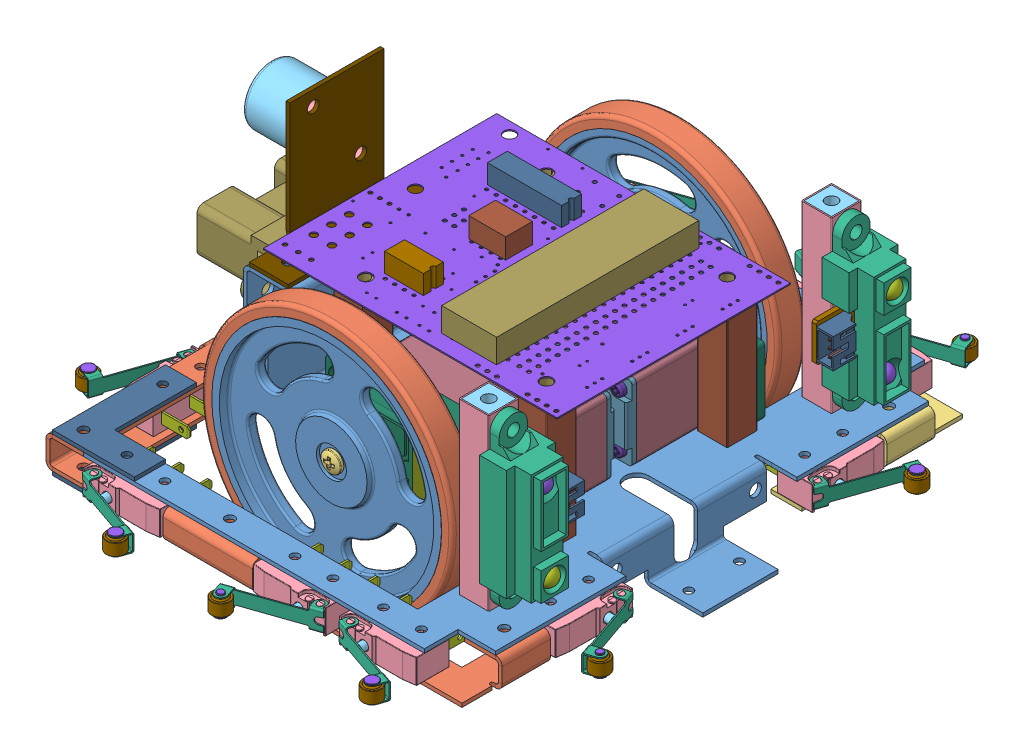
SolidWorks assembly SALbot, configuration Default. Lengths in mm.
Overall size (139.7 93.66 163.86).
225 component instances, 69 part files, 50 mates.
Components (placement in the parent):
- Chassis_alternativo-1: Chassis_alternativo [Default] at (-2.6157 -5.2715 -10.4768) size (139.7 34.48 163.86)
  - Chassis1_alternativa-1: Chassis1_alternativa [Default] at (-16.5911 3.3668 6.4675) size (122.56 34.48 132.92)
  - Chassis1_alternativa_1-1: Chassis1_alternativa_1 [Default] at (3.1589 -4.1332 51.6075) size (112.22 8.5 50.92)
  - Chassis1_alternativa_2-1: Chassis1_alternativa_2 [Default] at (3.1589 -3.1332 -38.6725) x (1 0 0) z (0 0 -1) size (112.22 8.5 50.92)
  - Switch-1: Switch [Default] at (-30.7928 -1.6984 -57.0433) x (1 0 0) z (0 1 0) size (22.89 29.47 6.5)
    - corpo-1: corpo [Default] at (1.1317 -3.5508 1.8152) size (19.85 9.5 6.5)
    - botao-1: botao [Default] at (-1.9933 4.9492 1.8152) size (2.28 2.9 2.2)
    - haste-1: haste [Default] at (1.6775 9.3883 1.8152) x (-0.945111 -0.326749 0) z (0 0 -1) size (21.6 7.58 5.4)
    - pinsw-1: pinsw [Default] at (-6.3683 -11.0508 1.8152) x (0 0 -1) z (1 0 0) size (2.85 8.5 0.5)
    - pino_haste-1: pino_haste [Default] at (9.4909 15.2506 1.8152) x (-0.923728 -0.383049 0) z (0 0 -1) size (3.2 3.2 5.25)
    - roda-1: roda [Default] at (9.4909 15.2506 1.8152) x (-0.923728 -0.383049 0) z (0 0 -1) size (4.85 4.85 3.95)
    - pinsw-3: pinsw [Default] at (1.1317 -11.0508 1.8152) x (0 0 -1) z (1 0 0) size (2.85 8.5 0.5)
    - pinsw-5: pinsw [Default] at (8.6317 -11.0508 1.8152) x (0 0 -1) z (1 0 0) size (2.85 8.5 0.5)
  - Switch-2: Switch [Default] at (16.1106 1.932 -57.0433) x (-1 0 0) z (0 -1 0) size (22.89 29.47 6.5)
    - corpo-1: corpo [Default] at (1.1317 -3.5508 1.8152) size (19.85 9.5 6.5)
    - botao-1: botao [Default] at (-1.9933 4.9492 1.8152) size (2.28 2.9 2.2)
    - haste-1: haste [Default] at (1.6775 9.3883 1.8152) x (-0.945111 -0.326749 0) z (0 0 -1) size (21.6 7.58 5.4)
    - pinsw-1: pinsw [Default] at (-6.3683 -11.0508 1.8152) x (0 0 -1) z (1 0 0) size (2.85 8.5 0.5)
    - pino_haste-1: pino_haste [Default] at (9.4909 15.2506 1.8152) x (-0.923728 -0.383049 0) z (0 0 -1) size (3.2 3.2 5.25)
    - roda-1: roda [Default] at (9.4909 15.2506 1.8152) x (-0.923728 -0.383049 0) z (0 0 -1) size (4.85 4.85 3.95)
    - pinsw-3: pinsw [Default] at (1.1317 -11.0508 1.8152) x (0 0 -1) z (1 0 0) size (2.85 8.5 0.5)
    - pinsw-5: pinsw [Default] at (8.6317 -11.0508 1.8152) x (0 0 -1) z (1 0 0) size (2.85 8.5 0.5)
  - Switch-3: Switch [Default] at (55.4648 -1.6984 39.0858) x (0 0 1) z (0 1 0) size (22.89 29.47 6.5)
    - corpo-1: corpo [Default] at (1.1317 -3.5508 1.8152) size (19.85 9.5 6.5)
    - botao-1: botao [Default] at (-1.9933 4.9492 1.8152) size (2.28 2.9 2.2)
    - haste-1: haste [Default] at (1.6775 9.3883 1.8152) x (-0.945111 -0.326749 0) z (0 0 -1) size (21.6 7.58 5.4)
    - pinsw-1: pinsw [Default] at (-6.3683 -11.0508 1.8152) x (0 0 -1) z (1 0 0) size (2.85 8.5 0.5)
    - pino_haste-1: pino_haste [Default] at (9.4909 15.2506 1.8152) x (-0.923728 -0.383049 0) z (0 0 -1) size (3.2 3.2 5.25)
    - roda-1: roda [Default] at (9.4909 15.2506 1.8152) x (-0.923728 -0.383049 0) z (0 0 -1) size (4.85 4.85 3.95)
    - pinsw-3: pinsw [Default] at (1.1317 -11.0508 1.8152) x (0 0 -1) z (1 0 0) size (2.85 8.5 0.5)
    - pinsw-5: pinsw [Default] at (8.6317 -11.0508 1.8152) x (0 0 -1) z (1 0 0) size (2.85 8.5 0.5)
  - Switch-4: Switch [Default] at (37.3472 -1.6984 -57.0433) x (1 0 0) z (0 1 0) size (22.89 29.47 6.5)
    - corpo-1: corpo [Default] at (1.1317 -3.5508 1.8152) size (19.85 9.5 6.5)
    - botao-1: botao [Default] at (-1.9933 4.9492 1.8152) size (2.28 2.9 2.2)
    - haste-1: haste [Default] at (1.6775 9.3883 1.8152) x (-0.945111 -0.326749 0) z (0 0 -1) size (21.6 7.58 5.4)
    - pinsw-1: pinsw [Default] at (-6.3683 -11.0508 1.8152) x (0 0 -1) z (1 0 0) size (2.85 8.5 0.5)
    - pino_haste-1: pino_haste [Default] at (9.4909 15.2506 1.8152) x (-0.923728 -0.383049 0) z (0 0 -1) size (3.2 3.2 5.25)
    - roda-1: roda [Default] at (9.4909 15.2506 1.8152) x (-0.923728 -0.383049 0) z (0 0 -1) size (4.85 4.85 3.95)
    - pinsw-3: pinsw [Default] at (1.1317 -11.0508 1.8152) x (0 0 -1) z (1 0 0) size (2.85 8.5 0.5)
    - pinsw-5: pinsw [Default] at (8.6317 -11.0508 1.8152) x (0 0 -1) z (1 0 0) size (2.85 8.5 0.5)
  - Switch-5: Switch [Default] at (-30.7928 1.932 69.9784) x (1 0 0) z (0 -1 0) size (22.89 29.47 6.5)
    - corpo-1: corpo [Default] at (1.1317 -3.5508 1.8152) size (19.85 9.5 6.5)
    - botao-1: botao [Default] at (-1.9933 4.9492 1.8152) size (2.28 2.9 2.2)
    - haste-1: haste [Default] at (1.6775 9.3883 1.8152) x (-0.945111 -0.326749 0) z (0 0 -1) size (21.6 7.58 5.4)
    - pinsw-1: pinsw [Default] at (-6.3683 -11.0508 1.8152) x (0 0 -1) z (1 0 0) size (2.85 8.5 0.5)
    - pino_haste-1: pino_haste [Default] at (9.4909 15.2506 1.8152) x (-0.923728 -0.383049 0) z (0 0 -1) size (3.2 3.2 5.25)
    - roda-1: roda [Default] at (9.4909 15.2506 1.8152) x (-0.923728 -0.383049 0) z (0 0 -1) size (4.85 4.85 3.95)
    - pinsw-3: pinsw [Default] at (1.1317 -11.0508 1.8152) x (0 0 -1) z (1 0 0) size (2.85 8.5 0.5)
    - pinsw-5: pinsw [Default] at (8.6317 -11.0508 1.8152) x (0 0 -1) z (1 0 0) size (2.85 8.5 0.5)
  - Switch-6: Switch [Default] at (37.3472 1.932 69.9784) x (1 0 0) z (0 -1 0) size (22.89 29.47 6.5)
    - corpo-1: corpo [Default] at (1.1317 -3.5508 1.8152) size (19.85 9.5 6.5)
    - botao-1: botao [Default] at (-1.9933 4.9492 1.8152) size (2.28 2.9 2.2)
    - haste-1: haste [Default] at (1.6775 9.3883 1.8152) x (-0.945111 -0.326749 0) z (0 0 -1) size (21.6 7.58 5.4)
    - pinsw-1: pinsw [Default] at (-6.3683 -11.0508 1.8152) x (0 0 -1) z (1 0 0) size (2.85 8.5 0.5)
    - pino_haste-1: pino_haste [Default] at (9.4909 15.2506 1.8152) x (-0.923728 -0.383049 0) z (0 0 -1) size (3.2 3.2 5.25)
    - roda-1: roda [Default] at (9.4909 15.2506 1.8152) x (-0.923728 -0.383049 0) z (0 0 -1) size (4.85 4.85 3.95)
    - pinsw-3: pinsw [Default] at (1.1317 -11.0508 1.8152) x (0 0 -1) z (1 0 0) size (2.85 8.5 0.5)
    - pinsw-5: pinsw [Default] at (8.6317 -11.0508 1.8152) x (0 0 -1) z (1 0 0) size (2.85 8.5 0.5)
  - Switch-7: Switch [Default] at (55.4648 1.932 -26.1507) x (0 0 -1) z (0 -1 0) size (22.89 29.47 6.5)
    - corpo-1: corpo [Default] at (1.1317 -3.5508 1.8152) size (19.85 9.5 6.5)
    - botao-1: botao [Default] at (-1.9933 4.9492 1.8152) size (2.28 2.9 2.2)
    - haste-1: haste [Default] at (1.6775 9.3883 1.8152) x (-0.945111 -0.326749 0) z (0 0 -1) size (21.6 7.58 5.4)
    - pinsw-1: pinsw [Default] at (-6.3683 -11.0508 1.8152) x (0 0 -1) z (1 0 0) size (2.85 8.5 0.5)
    - pino_haste-1: pino_haste [Default] at (9.4909 15.2506 1.8152) x (-0.923728 -0.383049 0) z (0 0 -1) size (3.2 3.2 5.25)
    - roda-1: roda [Default] at (9.4909 15.2506 1.8152) x (-0.923728 -0.383049 0) z (0 0 -1) size (4.85 4.85 3.95)
    - pinsw-3: pinsw [Default] at (1.1317 -11.0508 1.8152) x (0 0 -1) z (1 0 0) size (2.85 8.5 0.5)
    - pinsw-5: pinsw [Default] at (8.6317 -11.0508 1.8152) x (0 0 -1) z (1 0 0) size (2.85 8.5 0.5)
  - Switch-8: Switch [Default] at (16.1106 -1.6984 69.9784) x (-1 0 0) z (0 1 0) size (22.89 29.47 6.5)
    - corpo-1: corpo [Default] at (1.1317 -3.5508 1.8152) size (19.85 9.5 6.5)
    - botao-1: botao [Default] at (-1.9933 4.9492 1.8152) size (2.28 2.9 2.2)
    - haste-1: haste [Default] at (1.6775 9.3883 1.8152) x (-0.945111 -0.326749 0) z (0 0 -1) size (21.6 7.58 5.4)
    - pinsw-1: pinsw [Default] at (-6.3683 -11.0508 1.8152) x (0 0 -1) z (1 0 0) size (2.85 8.5 0.5)
    - pino_haste-1: pino_haste [Default] at (9.4909 15.2506 1.8152) x (-0.923728 -0.383049 0) z (0 0 -1) size (3.2 3.2 5.25)
    - roda-1: roda [Default] at (9.4909 15.2506 1.8152) x (-0.923728 -0.383049 0) z (0 0 -1) size (4.85 4.85 3.95)
    - pinsw-3: pinsw [Default] at (1.1317 -11.0508 1.8152) x (0 0 -1) z (1 0 0) size (2.85 8.5 0.5)
    - pinsw-5: pinsw [Default] at (8.6317 -11.0508 1.8152) x (0 0 -1) z (1 0 0) size (2.85 8.5 0.5)
  - Switch-9: Switch [Default] at (-47.3936 -1.6984 -28.6907) x (0 0 -1) z (0 1 0) size (22.89 29.47 6.5)
    - corpo-1: corpo [Default] at (1.1317 -3.5508 1.8152) size (19.85 9.5 6.5)
    - botao-1: botao [Default] at (-1.9933 4.9492 1.8152) size (2.28 2.9 2.2)
    - haste-1: haste [Default] at (1.6775 9.3883 1.8152) x (-0.945111 -0.326749 0) z (0 0 -1) size (21.6 7.58 5.4)
    - pinsw-1: pinsw [Default] at (-6.3683 -11.0508 1.8152) x (0 0 -1) z (1 0 0) size (2.85 8.5 0.5)
    - pino_haste-1: pino_haste [Default] at (9.4909 15.2506 1.8152) x (-0.923728 -0.383049 0) z (0 0 -1) size (3.2 3.2 5.25)
    - roda-1: roda [Default] at (9.4909 15.2506 1.8152) x (-0.923728 -0.383049 0) z (0 0 -1) size (4.85 4.85 3.95)
    - pinsw-3: pinsw [Default] at (1.1317 -11.0508 1.8152) x (0 0 -1) z (1 0 0) size (2.85 8.5 0.5)
    - pinsw-5: pinsw [Default] at (8.6317 -11.0508 1.8152) x (0 0 -1) z (1 0 0) size (2.85 8.5 0.5)
  - Switch-10: Switch [Default] at (-47.3936 1.932 41.6258) x (0 0 1) z (0 -1 0) size (22.89 29.47 6.5)
    - corpo-1: corpo [Default] at (1.1317 -3.5508 1.8152) size (19.85 9.5 6.5)
    - botao-1: botao [Default] at (-1.9933 4.9492 1.8152) size (2.28 2.9 2.2)
    - haste-1: haste [Default] at (1.6775 9.3883 1.8152) x (-0.945111 -0.326749 0) z (0 0 -1) size (21.6 7.58 5.4)
    - pinsw-1: pinsw [Default] at (-6.3683 -11.0508 1.8152) x (0 0 -1) z (1 0 0) size (2.85 8.5 0.5)
    - pino_haste-1: pino_haste [Default] at (9.4909 15.2506 1.8152) x (-0.923728 -0.383049 0) z (0 0 -1) size (3.2 3.2 5.25)
    - roda-1: roda [Default] at (9.4909 15.2506 1.8152) x (-0.923728 -0.383049 0) z (0 0 -1) size (4.85 4.85 3.95)
    - pinsw-3: pinsw [Default] at (1.1317 -11.0508 1.8152) x (0 0 -1) z (1 0 0) size (2.85 8.5 0.5)
    - pinsw-5: pinsw [Default] at (8.6317 -11.0508 1.8152) x (0 0 -1) z (1 0 0) size (2.85 8.5 0.5)
  - Chassis1_alternativa_3_4-3: Chassis1_alternativa_3_4 [Default] at (-41.7769 4.3668 54.7413) size (21.75 1 30)
  - Chassis1_alternativa_3_4-4: Chassis1_alternativa_3_4 [Default] at (-41.7758 -5.1332 54.7417) x (1 0 0.000081) z (-0.000081 0 1) size (21.75 1 30)
  - Chassis1_alternativa_3_4-5: Chassis1_alternativa_3_4 [Default] at (-41.7758 -4.1332 -41.8066) x (1 0 -0.000081) z (-0.000081 0 -1) size (21.75 1 30)
  - Chassis1_alternativa_3_4-6: Chassis1_alternativa_3_4 [Default] at (-41.7769 5.3668 -41.8063) x (1 0 0) z (0 0 -1) size (21.75 1 30)
- Standoff-1: Standoff [Default] at (35.0743 17.6731 19.6123) size (8 35 8)
  - Standoff1-2: Standoff1 [Default] at (0.7189 -18.5778 0.3784) size (8 35 8)
  - Standoff2-1: Standoff2 [Default] at (0.7189 -18.5778 0.3784) size (7.3 35 7.3)
- Standoff-2: Standoff [Default] at (35.0743 17.6731 -28.3877) size (8 35 8)
  - Standoff1-2: Standoff1 [Default] at (0.7189 -18.5778 0.3784) size (8 35 8)
  - Standoff2-1: Standoff2 [Default] at (0.7189 -18.5778 0.3784) size (7.3 35 7.3)
- Standoff-3: Standoff [Default] at (-13.5757 17.6731 -28.3877) size (8 35 8)
  - Standoff1-2: Standoff1 [Default] at (0.7189 -18.5778 0.3784) size (8 35 8)
  - Standoff2-1: Standoff2 [Default] at (0.7189 -18.5778 0.3784) size (7.3 35 7.3)
- Standoff-4: Standoff [Default] at (-13.5757 17.6731 19.6123) size (8 35 8)
  - Standoff1-2: Standoff1 [Default] at (0.7189 -18.5778 0.3784) size (8 35 8)
  - Standoff2-1: Standoff2 [Default] at (0.7189 -18.5778 0.3784) size (7.3 35 7.3)
- Futaba_S3003-1: Futaba_S3003 [Default] at (13.8176 5.7922 6.5039) x (-1 0 0) z (0 1 0) size (55.65 42.02 19.9)
  - Servo_meio-1: Servo_meio [Default] at (2.3494 -6.6132 3.2532) size (42.65 22.6 19.9)
  - Servo_base-2: Servo_base [Default] at (2.3494 -6.6132 3.2532) x (0 1 0) z (-1 0 0) size (3.45 19.9 42.65)
  - Servo_topo-1: Servo_topo [Default] at (2.3494 14.9868 3.2532) size (55.65 13.75 19.9)
  - Servo_logo-2: Servo_logo [Default] at (-4.8185 26.4868 3.2532) x (0 0 1) z (-1 0 0) size (16 0.5 10)
  - Servo_parafuso-1: Servo_parafuso [Default] at (-14.9756 5.3868 -3.6968) x (0 -1 0) z (0 0 1) size (29 3.3 3.3)
  - Servo_parafuso-2: Servo_parafuso [Default] at (19.6744 5.3868 -3.6968) x (0 -1 0) z (0 0 1) size (29 3.3 3.3)
  - Servo_parafuso-3: Servo_parafuso [Default] at (-14.9756 5.3868 10.2032) x (0 -1 0) z (0 0 1) size (29 3.3 3.3)
  - Servo_parafuso-4: Servo_parafuso [Default] at (19.6744 5.3868 10.2032) x (0 -1 0) z (0 0 1) size (29 3.3 3.3)
  - Servo_saida-1: Servo_saida [Default] at (13.3815 24.4868 3.2532) size (11 8.41 11)
- Futaba_S3003-2: Futaba_S3003 [Default] at (13.8176 12.2985 -14.5225) x (-1 0 0) z (0 -1 0) size (55.65 42.02 19.9)
  - Servo_meio-1: Servo_meio [Default] at (2.3494 -6.6132 3.2532) size (42.65 22.6 19.9)
  - Servo_base-2: Servo_base [Default] at (2.3494 -6.6132 3.2532) x (0 1 0) z (-1 0 0) size (3.45 19.9 42.65)
  - Servo_topo-1: Servo_topo [Default] at (2.3494 14.9868 3.2532) size (55.65 13.75 19.9)
  - Servo_logo-2: Servo_logo [Default] at (-4.8185 26.4868 3.2532) x (0 0 1) z (-1 0 0) size (16 0.5 10)
  - Servo_parafuso-1: Servo_parafuso [Default] at (-14.9756 5.3868 -3.6968) x (0 -1 0) z (0 0 1) size (29 3.3 3.3)
  - Servo_parafuso-2: Servo_parafuso [Default] at (19.6744 5.3868 -3.6968) x (0 -1 0) z (0 0 1) size (29 3.3 3.3)
  - Servo_parafuso-3: Servo_parafuso [Default] at (-14.9756 5.3868 10.2032) x (0 -1 0) z (0 0 1) size (29 3.3 3.3)
  - Servo_parafuso-4: Servo_parafuso [Default] at (19.6744 5.3868 10.2032) x (0 -1 0) z (0 0 1) size (29 3.3 3.3)
  - Servo_saida-1: Servo_saida [Default] at (13.3815 24.4868 3.2532) size (11 8.41 11)
- Roda-1: Roda [Default] at (1.7044 11.2317 38.6599) x (0.130526 0.991445 0) z (0 0 1) size (66.8 66.8 7.56)
  - Roda1-1: Roda1 [Default] at (-2.3333 0.9721 0.5708) size (65 65 7.5)
  - Roda2-1: Roda2 [Default] at (-2.3333 0.9721 0.5708) size (66.8 66.8 7.5)
- Roda-2: Roda [Default] at (-2.0068 9.6945 -46.6785) x (-0.793353 0.608761 0) z (0 0 -1) size (66.8 66.8 7.56)
  - Roda1-1: Roda1 [Default] at (-2.3333 0.9721 0.5708) size (65 65 7.5)
  - Roda2-1: Roda2 [Default] at (-2.3333 0.9721 0.5708) size (66.8 66.8 7.5)
- Parafuso_Servo-1: Parafuso_Servo [Default] at (0.4361 9.0453 -46.0093) x (0 0 -1) z (0.08396 -0.996469 0) size (9.26 5.35 5.35)
- Parafuso_Servo-2: Parafuso_Servo [Default] at (0.4361 9.0453 37.9907) x (0 0 1) z (-0.054189 -0.998531 0) size (9.26 5.35 5.35)
- Standoff_sensor-1: Standoff_sensor [Default] at (42.7947 20.8996 40.5654) size (8 45 8)
  - Standoff1_sensor-1: Standoff1_sensor [Default] at (-1.0016 -21.8043 0.7353) size (8 45 8)
  - Standoff2_sensor-1: Standoff2_sensor [Default] at (-1.0016 -21.8043 0.7353) size (7.3 45 7.3)
- Standoff_sensor-2: Standoff_sensor [Default] at (42.7947 20.8996 -50.4546) size (8 45 8)
  - Standoff1_sensor-1: Standoff1_sensor [Default] at (-1.0016 -21.8043 0.7353) size (8 45 8)
  - Standoff2_sensor-1: Standoff2_sensor [Default] at (-1.0016 -21.8043 0.7353) size (7.3 45 7.3)
- GP2D12-1: GP2D12 [Default] at (49.3222 20.1151 -48.3121) x (0 -1 0) z (0 0 1) size (44.5 14 19)
  - GP2D12_1-1: GP2D12_1 [Default] at (-1.4802 -3.529 -1.4072) size (44.5 13.5 13)
  - GP2D12_2-1: GP2D12_2 [Default] at (-11.8552 3.971 -1.4072) x (1 0 0) z (0 1 0) size (5 5 6.5)
  - GP2D12_3-1: GP2D12_3 [Default] at (8.6198 5.971 -1.4072) x (0.999097 0 0.042476) z (0 1 0) size (4.5 4.5 5)
  - GP2D12_5-1: GP2D12_5 [Default] at (-1.4802 0.921 -1.4072) x (-1 0 0) z (0 0 1) size (28 1.2 18.5)
  - GP2D12_4-1: GP2D12_4 [Default] at (-1.4302 3.171 5.0928) x (-1 0 0) z (0 1 0) size (7.9 7.6 4.5)
  - GP2D12_6-2: GP2D12_6 [Default] at (-1.4802 1.221 10.5928) size (4.5 2.75 6.5)
- GP2D12-2: GP2D12 [Default] at (49.3222 23.0755 39.8935) x (0 1 0) z (0 0 -1) size (44.5 14 19)
  - GP2D12_1-1: GP2D12_1 [Default] at (-1.4802 -3.529 -1.4072) size (44.5 13.5 13)
  - GP2D12_2-1: GP2D12_2 [Default] at (-11.8552 3.971 -1.4072) x (1 0 0) z (0 1 0) size (5 5 6.5)
  - GP2D12_3-1: GP2D12_3 [Default] at (8.6198 5.971 -1.4072) x (0.999097 0 0.042476) z (0 1 0) size (4.5 4.5 5)
  - GP2D12_5-1: GP2D12_5 [Default] at (-1.4802 0.921 -1.4072) x (-1 0 0) z (0 0 1) size (28 1.2 18.5)
  - GP2D12_4-1: GP2D12_4 [Default] at (-1.4302 3.171 5.0928) x (-1 0 0) z (0 1 0) size (7.9 7.6 4.5)
  - GP2D12_6-2: GP2D12_6 [Default] at (-1.4802 1.221 10.5928) size (4.5 2.75 6.5)
- GP2Y0A02YK0F-1: GP2Y0A02YK0F [Default] at (-54.5901 11.5624 -5.6439) x (0 0 1) z (0 -1 0) size (44.5 21.6 18.95)
  - GP2Y0A02K_1-1: GP2Y0A02K_1 [Default] at (1.6346 -9.8833 -1.4854) size (44.5 21.6 13)
  - GP2Y0A02K_2-1: GP2Y0A02K_2 [Default] at (11.1596 0.2167 -1.4854) x (1 0 0) z (0 1 0) size (8.95 9.4 11.5)
  - GP2Y0A02K_4-1: GP2Y0A02K_4 [Default] at (1.6846 -3.1833 4.9646) x (-1 0 0) z (0 1 0) size (7.9 7.6 4.5)
  - GP2Y0A02K_5-1: GP2Y0A02K_5 [Default] at (1.6346 -5.4333 -1.5354) x (-1 0 0) z (0 0 1) size (28 1.2 18.5)
  - GP2Y0A02K_6-1: GP2Y0A02K_6 [Default] at (1.6346 -5.1333 10.4646) size (4.5 2.75 6.5)
  - GP2Y0A02K_3-2: GP2Y0A02K_3 [Default] at (-8.6404 -0.0333 -1.4854) x (1 0 0) z (0 1 0) size (7.45 9.4 9.9)
- us_support2-1: us_support2 [Default] at (-37.9568 21.3627 -4.0093) x (0 0 1) z (-1 0 0) size (48 31.51 12.04)
- LV-EZ0-1: LV-EZ0 [Default] at (-45.6959 40.8048 -5.6285) x (0 0 1) z (0 1 0) size (19.9 16.44 22.1)
  - LV-EZ0_4-1: LV-EZ0_4 [Default] at (1.6393 -0.3975 -0.4339) size (19.9 1.25 22.1)
  - LV-EZ0_1-1: LV-EZ0_1 [Default] at (-8.2207 0.2775 6.3761) size (1.5 1.15 1.5)
  - LV-EZ0_2-1: LV-EZ0_2 [Default] at (-8.2207 0.2775 8.9161) size (1.5 1.15 1.5)
  - LV-EZ0_3-1: LV-EZ0_3 [Default] at (-4.6707 0.2775 -8.9339) size (4 1.15 4)
  - LV-EZ0_5-1: LV-EZ0_5 [Default] at (1.6393 -0.8975 -0.4339) x (1 0 0) z (0 0 -1) size (15.5 15.81 15.5)
  - LV-EZ0_6-1: LV-EZ0_6 [Default] at (1.6393 0.2275 -0.4339) x (-1 0 0) z (0 0 1) size (11 5 11)
  - LV-EZ0_7-1: LV-EZ0_7 [Default] at (1.6393 -3.7725 -0.4339) x (-1 0 0) z (0 0 1) size (8.56 2.06 8.56)
  - LV-EZ0_1-3: LV-EZ0_1 [Default] at (-8.2207 0.2775 3.8361) size (1.5 1.15 1.5)
  - LV-EZ0_1-5: LV-EZ0_1 [Default] at (-8.2207 0.2775 1.2961) size (1.5 1.15 1.5)
  - LV-EZ0_1-7: LV-EZ0_1 [Default] at (-8.2207 0.2775 -1.2439) size (1.5 1.15 1.5)
  - LV-EZ0_1-9: LV-EZ0_1 [Default] at (-8.2207 0.2775 -3.7839) size (1.5 1.15 1.5)
  - LV-EZ0_3-3: LV-EZ0_3 [Default] at (7.9293 0.2775 8.0661) size (4 1.15 4)
  - LV-EZ0_1-13: LV-EZ0_1 [Default] at (-8.2207 0.2775 -6.3239) size (1.5 1.15 1.5)
- placa_markiii-1: placa_markiii [Default] at (-111.4068 34.0953 -134.0093) x (0 0 1) z (0 1 0) size (62 78 6.67)
  - markiii-1: markiii [Default] at origin size (62 78 0.32)
  - PH Header_JST B3BPHKS(LF)(SN)-1: PH Header_JST B3BPHKS(LF)(SN) [Default] at (112 154 0.32) size (7.9 4.5 0)
  - PH Header_JST B3BPHKS(LF)(SN)-2: PH Header_JST B3BPHKS(LF)(SN) [Default] at (148 154 0.32) size (7.9 4.5 0)
  - PH Header_JST B3BPHKS(LF)(SN)-3: PH Header_JST B3BPHKS(LF)(SN) [Default] at (136 154 0.32) size (7.9 4.5 0)
  - PH Header_JST B3BPHKS(LF)(SN)-4: PH Header_JST B3BPHKS(LF)(SN) [Default] at (124 154 0.32) size (7.9 4.5 0)
  - TSW10407GS_SAMTEC TSW104XXXS-1: TSW10407GS_SAMTEC TSW104XXXS [Default] at (159.5 151.5 0.32) x (0 1 0) z (0 0 1) size (10.16 2.54 0)
  - TSW10407GS_SAMTEC TSW104XXXS-2: TSW10407GS_SAMTEC TSW104XXXS [Default] at (100.5 151.5 0.32) x (0 1 0) z (0 0 1) size (10.16 2.54 0)
  - 01 uF_KEMET C410C104M5U5CATR-1: 01 uF_KEMET C410C104M5U5CATR [Default] at (100.5 130 0.32) x (0 -1 0) z (0 0 1) size (4.4 2.54 0)
  - 01 uF_KEMET C410C104M5U5CATR-2: 01 uF_KEMET C410C104M5U5CATR [Default] at (136 97 0.32) x (0 1 0) z (0 0 1) size (4.4 2.54 0)
  - 01 uF_KEMET C410C104M5U5CATR-3: 01 uF_KEMET C410C104M5U5CATR [Default] at (145.5 113.5 0.32) size (4.4 2.54 0)
  - 01 uF_KEMET C410C104M5U5CATR-4: 01 uF_KEMET C410C104M5U5CATR [Default] at (108 94 0.32) x (-1 0 0) z (0 0 1) size (4.4 2.54 0)
  - 01 uF_KEMET C410C104M5U5CATR-5: 01 uF_KEMET C410C104M5U5CATR [Default] at (100.25 103 0.32) size (4.4 2.54 0)
  - 01 uF_KEMET C410C104M5U5CATR-6: 01 uF_KEMET C410C104M5U5CATR [Default] at (121 95 0.32) x (0 1 0) z (0 0 1) size (4.4 2.54 0)
  - 01 uF_KEMET C410C104M5U5CATR-7: 01 uF_KEMET C410C104M5U5CATR [Default] at (121 107 0.32) x (0 1 0) z (0 0 1) size (4.4 2.54 0)
  - 100 uF_PANASONIC ECA1CAK101X-1: 100 uF_PANASONIC ECA1CAK101X [Default] at (150 94.5 0.32) x (-1 0 0) z (0 0 1) size (6.5 6.5 0)
  - 100 uF_PANASONIC ECA1CAK101X-2: 100 uF_PANASONIC ECA1CAK101X [Default] at (157.5 103 0.32) x (0 1 0) z (0 0 1) size (6.5 6.5 0)
  - 33 uF_PANASONIC ECEA0JKS330-1: 33 uF_PANASONIC ECEA0JKS330 [Default] at (118 148 0.32) x (-1 0 0) z (0 0 1) size (9.16 5.6 0)
  - 33 uF_PANASONIC ECEA0JKS330-2: 33 uF_PANASONIC ECEA0JKS330 [Default] at (146 148 0.32) x (-1 0 0) z (0 0 1) size (9.16 5.6 0)
  - FAIRCHILD 1N4148_FAIRCHILD 1N4118-1: FAIRCHILD 1N4148_FAIRCHILD 1N4118 [Default] at (138.25 80 0.32) x (0 1 0) z (0 0 1) size (4.6 1.93 0)
  - RED_VISHAY TLLR4401-1: RED_VISHAY TLLR4401 [Default] at (158 120 0.32) x (0 -1 0) z (0 0 1) size (7.4 4.87 0)
  - TSW12023TD_SAMTEC TSW120XXXD-1: TSW12023TD_SAMTEC TSW120XXXD [Default] at (130 141.4 0.32) size (50.8 5.08 0)
  - TYCO 6404565_TYCO 6404565-1: TYCO 6404565_TYCO 6404565 [Default] at (134 85.5 0.32) x (0 1 0) z (0 0 1) size (12.7 5.72 0)
  - TSW10023TS_SAMTEC TSW103XXXS-1: TSW10023TS_SAMTEC TSW103XXXS [Default] at (100.5 137 0.32) x (0 -1 0) z (0 0 1) size (7.62 2.54 0)
  - TSW10023TS_SAMTEC TSW103XXXS-2: TSW10023TS_SAMTEC TSW103XXXS [Default] at (159.5 137 0.32) x (0 -1 0) z (0 0 1) size (7.62 2.54 0)
  - DB9F Vertical_TYCO 13383132-1: DB9F Vertical_TYCO 13383132 [Default] at (114.6 85.5 0.32) size (31.15 12.65 0)
  - TSW10326TD_SAMTEC103XXXD-1: TSW10326TD_SAMTEC103XXXD [Default] at (128 98 0.32) size (7.62 5.08 0)
  - Plug_PIN1-1: Plug_PIN1 [Default] at (128 116.5 0.32) size (2.8 2.8 0)
  - 1M_MULTICOMP MCF 025W 56R-1: 1M_MULTICOMP MCF 025W 56R [Default] at (134 119.5 0.32) size (9 2.7 0)
  - 75M_VISHAY MRS25 2M4-1: 75M_VISHAY MRS25 2M4 [Default] at (134 110 0.32) size (4.4 2.5 0)
  - 75M_VISHAY MRS25 2M4-2: 75M_VISHAY MRS25 2M4 [Default] at (141 97 0.32) x (0 1 0) z (0 0 1) size (4.4 2.5 0)
  - 1K_TYCO 116258752-1: 1K_TYCO 116258752 [Default] at (145.5 116.5 0.32) size (4.4 2.4 0)
  - 1K_TYCO 116258752-2: 1K_TYCO 116258752 [Default] at (153 119.5 0.32) x (-1 0 0) z (0 0 1) size (4.4 2.4 0)
  - 1K_TYCO 116258752-3: 1K_TYCO 116258752 [Default] at (135 133.25 0) x (0 -1 0) z (0 0 -1) size (4.4 2.4 0)
  - 1K_TYCO 116258752-4: 1K_TYCO 116258752 [Default] at (149 126 0) x (-1 0 0) z (0 0 -1) size (4.4 2.4 0)
  - C & K 1210M1S3CQE2_C & K 1201M1S3CQE2-1: C & K 1210M1S3CQE2_C & K 1201M1S3CQE2 [Default] at (146.5 85 0.32) x (-1 0 0) z (0 0 1) size (12.7 11.43 0)
  - OMRON B3F1002_OMRON B3F1002-1: OMRON B3F1002_OMRON B3F1002 [Default] at (104 111 0.32) x (0 1 0) z (0 0 1) size (9 8 0)
  - WIELAND ELECTRIC 2519503530_WIELAND ELECTRIC 2519503530-1: WIELAND ELECTRIC 2519503530_WIELAND ELECTRIC 2519503530 [Default] at (157.25 84.5 0.32) x (0 1 0) z (0 0 1) size (10.5 7.2 0)
  - MAX667CPA_JA8-1: MAX667CPA_JA8 [Default] at (148 106 0.32) x (0 -1 0) z (0 0 1) size (10.3 5.3 5.08)
  - MAX232ACPE_PE16A-1: MAX232ACPE_PE16A [Default] at (114 104 0.32) x (0 -1 0) z (0 0 1) size (19.7 5.3 5.08)
  - 24LC32AP_PDIP300P8-1: 24LC32AP_PDIP300P8 [Default] at (128 109 0.32) size (7.1 9.8 5.34)
  - 20000 MHz_AEL CRYSTALS C20M000000L01-1: 20000 MHz_AEL CRYSTALS C20M000000L01 [Default] at (138 115 0.32) size (10 5 0)
  - PIC18F4620IP_PDIP600P40-1: PIC18F4620IP_PDIP600P40 [Default] at (130 129.5 0.32) x (0 1 0) z (0 0 1) size (14.6 53.7 6.35)
  - 47K_MULTICOMP MF12 4K7-1: 47K_MULTICOMP MF12 4K7 [Default] at (149 129.5 0) x (-1 0 0) z (0 0 -1) size (4.8 1.85 0)
  - 47K_MULTICOMP MF12 4K7-2: 47K_MULTICOMP MF12 4K7 [Default] at (149 133 0) x (-1 0 0) z (0 0 -1) size (4.8 1.85 0)
Mates (geometry in assembly coordinates):
- Coincident1: coincident anti-aligned: plane of Chassis_alternativo-1/Chassis1_alternativa-1 through (45.7932 -0.9047 -26.0093) normal (0 1 0); plane of Standoff-3/Standoff2-1 through (-9.2068 -0.9047 -31.6593) normal (0 -1 0)
- Coincident2: coincident anti-aligned: plane of Chassis_alternativo-1/Chassis1_alternativa-1 through (45.7932 -0.9047 -26.0093) normal (0 1 0); plane of Standoff-4/Standoff2-1 through (-9.2068 -0.9047 16.3407) normal (0 -1 0)
- Coincident3: coincident anti-aligned: plane of Chassis_alternativo-1/Chassis1_alternativa-1 through (45.7932 -0.9047 -26.0093) normal (0 1 0); plane of Standoff-1/Standoff2-1 through (39.4432 -0.9047 16.3407) normal (0 -1 0)
- Coincident4: coincident anti-aligned: plane of Chassis_alternativo-1/Chassis1_alternativa-1 through (45.7932 -0.9047 -26.0093) normal (0 1 0); plane of Standoff-2/Standoff2-1 through (39.4432 -0.9047 -31.6593) normal (0 -1 0)
- Concentric1: concentric aligned: cylinder of Chassis_alternativo-1/Chassis1_alternativa-1 through (-12.8568 -0.9047 -28.0093) axis (0 -1 0) radius 1.5875; cylinder of Standoff-3/Standoff2-1 through (-12.8568 34.0953 -28.0093) axis (0 -1 0) radius 1.5875
- Concentric2: concentric aligned: cylinder of Chassis_alternativo-1/Chassis1_alternativa-1 through (-12.8568 -0.9047 19.9907) axis (0 -1 0) radius 1.5875; cylinder of Standoff-4/Standoff2-1 through (-12.8568 34.0953 19.9907) axis (0 -1 0) radius 1.5875
- Concentric3: concentric aligned: cylinder of Chassis_alternativo-1/Chassis1_alternativa-1 through (35.7932 -0.9047 19.9907) axis (0 -1 0) radius 1.5875; cylinder of Standoff-1/Standoff2-1 through (35.7932 34.0953 19.9907) axis (0 -1 0) radius 1.5875
- Concentric4: concentric aligned: cylinder of Chassis_alternativo-1/Chassis1_alternativa-1 through (35.7932 -0.9047 -28.0093) axis (0 -1 0) radius 1.5875; cylinder of Standoff-2/Standoff2-1 through (35.7932 34.0953 -28.0093) axis (0 -1 0) radius 1.5875
- Parallel1: parallel aligned: plane of Chassis_alternativo-1/Chassis1_alternativa-1 through (35.7932 -0.9047 26.9907) normal (0 0 1); plane of Standoff-4/Standoff1-2 through (-8.8568 34.0953 23.9907) normal (0 0 1)
- Parallel2: parallel aligned: plane of Chassis_alternativo-1/Chassis1_alternativa-1 through (35.7932 -0.9047 26.9907) normal (0 0 1); plane of Standoff-1/Standoff1-2 through (39.7932 34.0953 23.9907) normal (0 0 1)
- Parallel3: parallel aligned: plane of Chassis_alternativo-1/Chassis1_alternativa-1 through (35.7932 -0.9047 -35.0093) normal (0 0 -1); plane of Standoff-3/Standoff1-2 through (-8.8568 34.0953 -32.0093) normal (0 0 -1)
- Parallel4: parallel aligned: plane of Chassis_alternativo-1/Chassis1_alternativa-1 through (35.7932 -0.9047 -35.0093) normal (0 0 -1); plane of Standoff-2/Standoff1-2 through (39.7932 34.0953 -32.0093) normal (0 0 -1)
- Coincident9: coincident anti-aligned: plane of Chassis_alternativo-1/Chassis1_alternativa-1 through (45.7932 -0.9047 -26.0093) normal (0 1 0); plane of Futaba_S3003-2/Servo_meio-1 through (30.7932 -0.9047 -29.5093) normal (0 -1 0)
- Coincident10: coincident anti-aligned: plane of Chassis_alternativo-1/Chassis1_alternativa-1 through (45.7932 -0.9047 -26.0093) normal (0 1 0); plane of Futaba_S3003-1/Servo_meio-1 through (30.7932 -0.9047 21.4907) normal (0 -1 0)
- Coincident11: coincident anti-aligned: plane of Futaba_S3003-2/Servo_topo-1 through (-15.3568 16.9953 -32.0093) normal (0 0 1); plane of Standoff-3/Standoff1-2 through (-8.8568 34.0953 -32.0093) normal (0 0 -1)
- Coincident12: coincident anti-aligned: plane of Futaba_S3003-1/Servo_topo-1 through (-15.3568 1.0953 23.9907) normal (0 0 -1); plane of Standoff-1/Standoff1-2 through (39.7932 34.0953 23.9907) normal (0 0 1)
- Coincident13: coincident anti-aligned: plane of Standoff-1/Standoff1-2 through (31.7932 34.0953 23.9907) normal (-1 0 0); plane of Futaba_S3003-1/Servo_meio-1 through (31.7932 17.9953 21.4907) normal (1 0 0)
- Coincident14: coincident anti-aligned: plane of Standoff-2/Standoff1-2 through (31.7932 34.0953 -24.0093) normal (-1 0 0); plane of Futaba_S3003-2/Servo_meio-1 through (31.7932 0.0953 -29.5093) normal (1 0 0)
- Concentric5: concentric anti-aligned: cylinder of Futaba_S3003-1/Servo_saida-1 through (0.4361 9.0453 34.3907) axis (0 0 1) radius 1; cylinder of Roda-1/Roda1-1 through (0.4361 9.0453 14.2307) axis (0 0 -1) radius 1
- Concentric6: concentric anti-aligned: cylinder of Roda-2/Roda1-1 through (0.4361 9.0453 -22.2493) axis (0 0 1) radius 1; cylinder of Futaba_S3003-2/Servo_saida-1 through (0.4361 9.0453 -42.4093) axis (0 0 -1) radius 1
- Parallel5: parallel aligned: plane of Futaba_S3003-2/Servo_saida-1 through (1.7122 11.5045 -43.4093) normal (0.953717 -0.300706 0); plane of Roda-2/Roda1-1 through (-0.7327 6.5322 -55.8784) normal (0.953717 -0.300706 0)
- Parallel6: parallel anti-aligned: plane of Futaba_S3003-1/Servo_saida-1 through (1.7122 11.5045 35.3907) normal (0.953717 -0.300706 0); plane of Roda-1/Roda1-1 through (1.6048 11.5585 47.8598) normal (-0.953717 0.300706 0)
- Coincident17: coincident anti-aligned: plane of Futaba_S3003-2/Servo_saida-1 through (0.4361 9.0453 -47.4093) normal (0 0 -1); plane of Roda-2/Roda1-1 through (2.1102 11.227 -47.4093) normal (0 0 1)
- Coincident18: coincident anti-aligned: plane of Futaba_S3003-1/Servo_saida-1 through (0.4361 9.0453 39.3907) normal (0 0 1); plane of Roda-1/Roda1-1 through (-2.2904 9.4043 39.3907) normal (0 0 -1)
- Concentric7: concentric aligned: cylinder of Parafuso_Servo-2 through (0.4361 9.0453 33.3407) axis (0 0 -1) radius 1; cylinder of Roda-1/Roda1-1 through (0.4361 9.0453 14.2307) axis (0 0 -1) radius 1
- Concentric8: concentric aligned: cylinder of Parafuso_Servo-1 through (0.4361 9.0453 -41.3593) axis (0 0 1) radius 1; cylinder of Roda-2/Roda1-1 through (0.4361 9.0453 -22.2493) axis (0 0 1) radius 1
- Coincident19: coincident anti-aligned: plane of Roda-2/Roda1-1 through (1.0448 9.8387 -48.9593) normal (0 0 -1); plane of Parafuso_Servo-1 through (0.3311 10.2909 -48.9593) normal (0 0 1)
- Coincident20: coincident anti-aligned: plane of Roda-1/Roda1-1 through (-0.5554 9.1759 40.9407) normal (0 0 1); plane of Parafuso_Servo-2 through (0.5038 10.2935 40.9407) normal (0 0 -1)
- Coincident21: coincident anti-aligned: plane of Chassis_alternativo-1/Chassis1_alternativa-1 through (45.7932 -0.9047 -26.0093) normal (0 1 0); plane of Standoff_sensor-1/Standoff2_sensor-1 through (45.4432 -0.9047 37.6507) normal (0 -1 0)
- Coincident22: coincident anti-aligned: plane of Chassis_alternativo-1/Chassis1_alternativa-1 through (45.7932 -0.9047 -26.0093) normal (0 1 0); plane of Standoff_sensor-2/Standoff2_sensor-1 through (45.4432 -0.9047 -53.3693) normal (0 -1 0)
- Concentric9: concentric aligned: cylinder of Chassis_alternativo-1/Chassis1_alternativa-1 through (41.7932 -0.9047 -49.7193) axis (0 -1 0) radius 1.5875; cylinder of Standoff_sensor-2/Standoff2_sensor-1 through (41.7932 44.0953 -49.7193) axis (0 -1 0) radius 1.5875
- Concentric10: concentric aligned: cylinder of Chassis_alternativo-1/Chassis1_alternativa-1 through (41.7932 -0.9047 41.3007) axis (0 -1 0) radius 1.5875; cylinder of Standoff_sensor-1/Standoff2_sensor-1 through (41.7932 44.0953 41.3007) axis (0 -1 0) radius 1.5875
- Coincident25: coincident anti-aligned: plane of Standoff_sensor-2/Standoff1_sensor-1 through (45.7932 44.0953 -45.7193) normal (1 0 0); plane of GP2D12-1/GP2D12_1-1 through (45.7932 36.3453 -43.2193) normal (-1 0 0)
- Concentric15: concentric anti-aligned: cylinder of Standoff_sensor-2/Standoff2_sensor-1 through (38.1432 3.0953 -49.7193) axis (1 0 0) radius 1.625; cylinder of GP2D12-1/GP2D12_1-1 through (51.2932 3.0953 -49.7193) axis (-1 0 0) radius 1.625
- Concentric16: concentric anti-aligned: cylinder of Standoff_sensor-2/Standoff2_sensor-1 through (38.1432 40.0953 -49.7193) axis (1 0 0) radius 1.625; cylinder of GP2D12-1/GP2D12_1-1 through (51.2932 40.0953 -49.7193) axis (-1 0 0) radius 1.625
- Coincident26: coincident anti-aligned: plane of Standoff_sensor-1/Standoff1_sensor-1 through (45.7932 44.0953 45.3007) normal (1 0 0); plane of GP2D12-2/GP2D12_1-1 through (45.7932 6.8453 34.8007) normal (-1 0 0)
- Concentric17: concentric anti-aligned: cylinder of Standoff_sensor-1/Standoff2_sensor-1 through (38.1432 3.0953 41.3007) axis (1 0 0) radius 1.625; cylinder of GP2D12-2/GP2D12_1-1 through (51.2932 3.0953 41.3007) axis (-1 0 0) radius 1.625
- Concentric18: concentric anti-aligned: cylinder of Standoff_sensor-1/Standoff2_sensor-1 through (38.1432 40.0953 41.3007) axis (1 0 0) radius 1.625; cylinder of GP2D12-2/GP2D12_1-1 through (51.2932 40.0953 41.3007) axis (-1 0 0) radius 1.625
- Coincident27: coincident anti-aligned: plane of Chassis_alternativo-1/Chassis1_alternativa-1 through (-44.7068 131.5378 -26.0093) normal (-1 0 0); plane of GP2Y0A02YK0F-1/GP2Y0A02K_1-1 through (-44.7068 6.5478 -18.7593) normal (1 0 0)
- Concentric19: concentric aligned: cylinder of Chassis_alternativo-1/Chassis1_alternativa-1 through (-44.7068 13.0478 -22.5093) axis (1 0 0) radius 1.625; cylinder of GP2Y0A02YK0F-1/GP2Y0A02K_1-1 through (-50.2068 13.0478 -22.5093) axis (1 0 0) radius 1.625
- Concentric20: concentric aligned: cylinder of Chassis_alternativo-1/Chassis1_alternativa-1 through (-44.7068 13.0478 14.4907) axis (1 0 0) radius 1.625; cylinder of GP2Y0A02YK0F-1/GP2Y0A02K_1-1 through (-50.2068 13.0478 14.4907) axis (1 0 0) radius 1.625
- Coincident28: coincident anti-aligned: plane of Chassis_alternativo-1/Chassis1_alternativa-1 through (66.999 21.3627 -26.0093) normal (0 1 0); plane of us_support2-1 through (-43.1068 21.3627 19.9907) normal (0 -1 0)
- Concentric21: concentric aligned: cylinder of Chassis_alternativo-1/Chassis1_alternativa-1 through (-37.9568 -13.1232 -22.8593) axis (0 1 0) radius 1.25; cylinder of us_support2-1 through (-37.9568 21.3617 -22.8593) axis (0 1 0) radius 1.25
- Concentric22: concentric aligned: cylinder of Chassis_alternativo-1/Chassis1_alternativa-1 through (-37.9568 -13.1232 14.8407) axis (0 1 0) radius 1.25; cylinder of us_support2-1 through (-37.9568 21.3617 14.8407) axis (0 1 0) radius 1.25
- Coincident30: coincident anti-aligned: plane of us_support2-1 through (-44.8434 21.1568 19.9907) normal (-1 0 0); plane of LV-EZ0-1/LV-EZ0_4-1 through (-44.8434 51.421 -15.0493) normal (1 0 0)
- Concentric25: concentric aligned: cylinder of us_support2-1 through (-43.8434 31.871 -10.2993) axis (-1 0 0) radius 1.55; cylinder of LV-EZ0-1/LV-EZ0_3-1 through (-44.8434 31.871 -10.2993) axis (-1 0 0) radius 1.55
- Concentric26: concentric aligned: cylinder of us_support2-1 through (-43.8434 48.871 2.3007) axis (-1 0 0) radius 1.55; cylinder of LV-EZ0-1/LV-EZ0_3-3 through (-44.8434 48.871 2.3007) axis (-1 0 0) radius 1.55
- Coincident31: coincident anti-aligned: plane of Standoff-1/Standoff2-1 through (39.4432 34.0953 16.3407) normal (0 1 0); plane of placa_markiii-1/markiii-1 through (-32.4068 34.0953 -35.0093) normal (0 -1 0)
- Concentric27: concentric aligned: cylinder of Standoff-1/Standoff2-1 through (35.7932 34.0953 19.9907) axis (0 -1 0) radius 1.5875; cylinder of placa_markiii-1/markiii-1 through (35.7932 34.4154 19.9907) axis (0 -1 0) radius 1.5875
- Concentric28: concentric aligned: cylinder of Standoff-2/Standoff2-1 through (35.7932 34.0953 -28.0093) axis (0 -1 0) radius 1.5875; cylinder of placa_markiii-1/markiii-1 through (35.7932 34.4154 -28.0093) axis (0 -1 0) radius 1.5875
